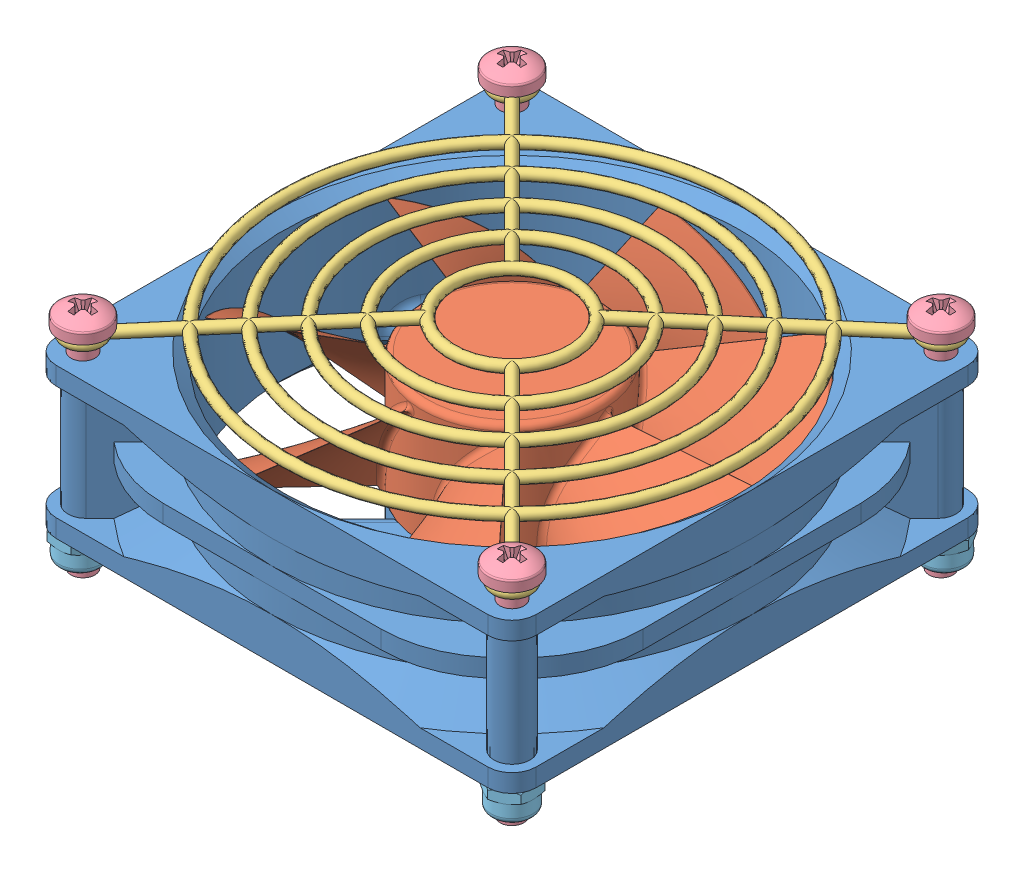
SolidWorks assembly 80 FanCooler-A, configuration Valor predeterminado. Lengths in mm.
Overall size (152.62 38.02 152.62).
11 component instances, 5 part files, 0 mates.
Components (placement in the parent):
- 80 FanCooler-Frame-1: 80 FanCooler-Frame [Valor predeterminado] at origin size (80 27 80)
- 80 FanCooler-Fan-1: 80 FanCooler-Fan [Valor predeterminado] at (0 14.5 0) x (0.4333 0 0.90125) z (-0.90125 0 0.4333) size (77.79 20.07 78.2)
- 80FanCooler-Guard-1: 80FanCooler-Guard [Valor predeterminado] at (0 26.9 0) x (0.707107 0 0.707107) z (-0.707107 0 0.707107) size (107.92 3.98 107.92)
- DIN EN ISO 7045 - M4 x 35 - Z - 35N-1: DIN EN ISO 7045 - M4 x 35 - Z - 35N [Valor predeterminado] at (35.75 31.8 -35.75) x (0 -1 0) z (-0.999963 0 -0.008587) size (38.02 8 8)
- DIN EN ISO 7045 - M4 x 35 - Z - 35N-2: DIN EN ISO 7045 - M4 x 35 - Z - 35N [Valor predeterminado] at (-35.75 31.8 -35.75) x (0 -1 0) z (-0.008587 0 0.999963) size (38.02 8 8)
- DIN EN ISO 7045 - M4 x 35 - Z - 35N-3: DIN EN ISO 7045 - M4 x 35 - Z - 35N [Valor predeterminado] at (-35.75 31.8 35.75) x (0 -1 0) z (0.999963 0 0.008587) size (38.02 8 8)
- DIN EN ISO 7045 - M4 x 35 - Z - 35N-4: DIN EN ISO 7045 - M4 x 35 - Z - 35N [Valor predeterminado] at (35.75 31.8 35.75) x (0 -1 0) z (0.008587 0 -0.999963) size (38.02 8 8)
- DIN EN ISO 10511 - M4 - N-1: DIN EN ISO 10511 - M4 - N [Valor predeterminado] at (-36 -1.95 -36) x (1 0 0) z (0 -1 0) size (7 8.08 5)
- DIN EN ISO 10511 - M4 - N-2: DIN EN ISO 10511 - M4 - N [Valor predeterminado] at (36 -1.95 36) x (-1 0 0) z (0 -1 0) size (7 8.08 5)
- DIN EN ISO 10511 - M4 - N-3: DIN EN ISO 10511 - M4 - N [Valor predeterminado] at (36 -1.95 -36) x (0 0 1) z (0 -1 0) size (7 8.08 5)
- DIN EN ISO 10511 - M4 - N-4: DIN EN ISO 10511 - M4 - N [Valor predeterminado] at (-36 -1.95 36) x (0 0 -1) z (0 -1 0) size (7 8.08 5)
